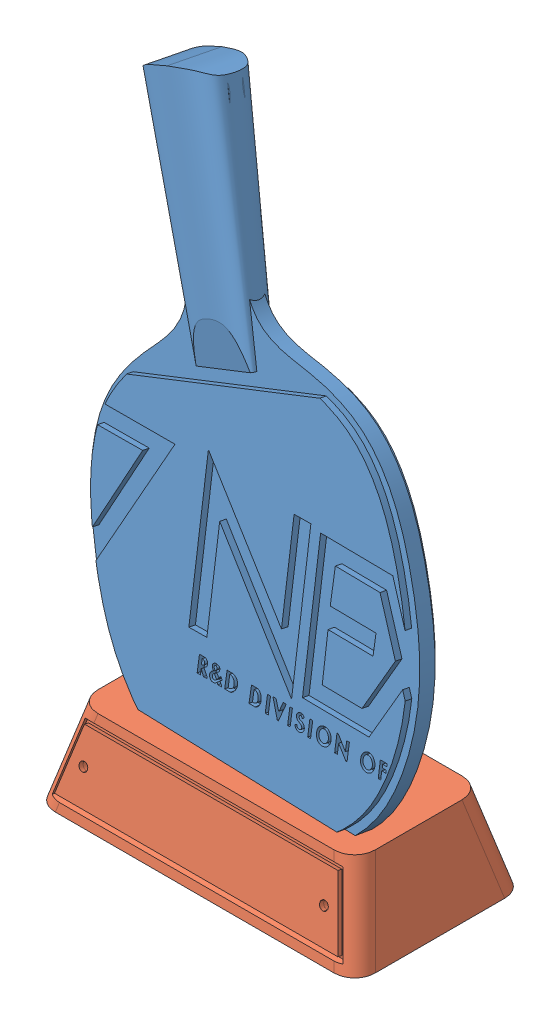
SolidWorks assembly Trophy20, configuration Default. Lengths in mm.
Overall size (242.14 310.08 84.07).
4 component instances, 4 part files, 0 mates.
Components (placement in the parent):
- Paddle10-1: Paddle10 [Default] at (-31.5659 98.2785 -17.6474) x (-0.936662 -0.34902 0.02915) z (-0.032077 0.168367 0.985202) size (156.24 272.12 27.81)
- Base-2: Base [Default] at (-20.9644 -21.7212 -17.5395) size (150 40 80)
- BaseWeight-1: BaseWeight [Default] at origin size (128 36 58) (hidden)
- ScrewHole^Trophy20-1: ScrewHole^Trophy20 [Default] at origin size (7 53.58 13.94) (hidden, virtual)
